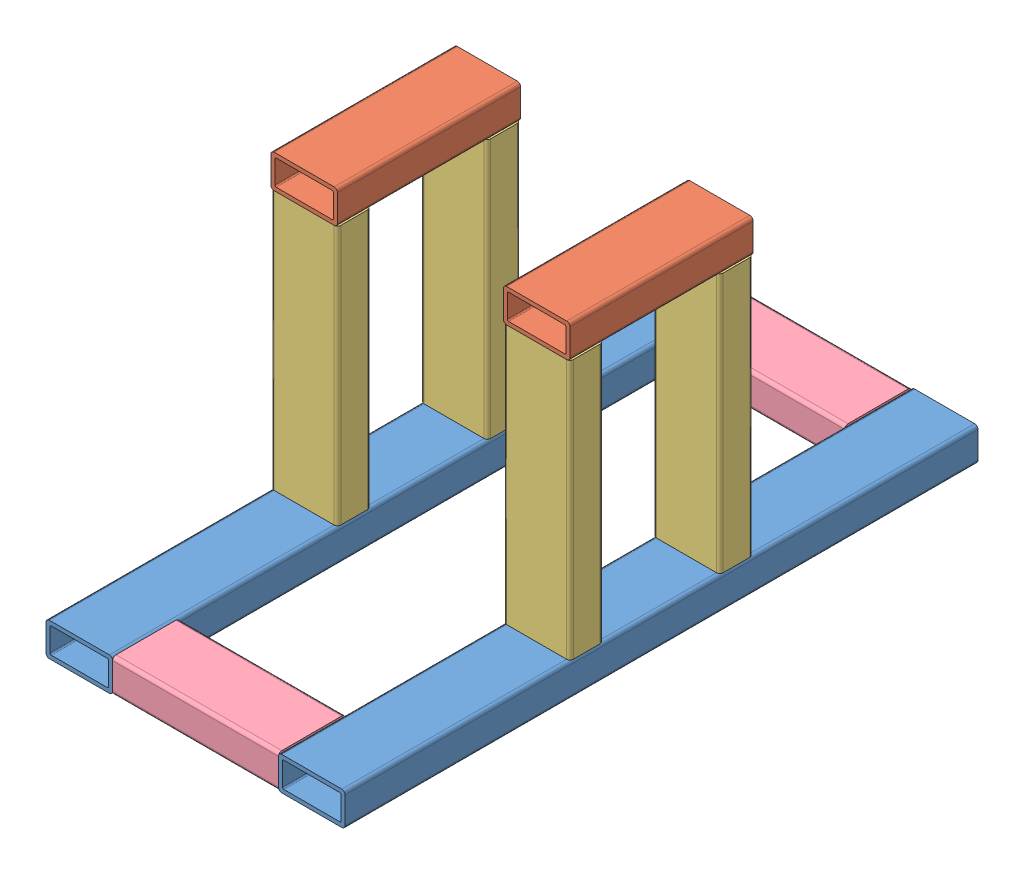
SolidWorks assembly Stand Assembly, configuration Default. Lengths in mm.
Overall size (228.08 248.72 482.6).
10 component instances, 4 part files, 29 mates.
Components (placement in the parent):
- Stand Assembly - 1 by 2 inch-1: Stand Assembly - 1 by 2 inch [6527K991] at (233.4487 297.5051 247.6284) size (50.8 25.4 482.6)
- Stand Assembly - 1 by 2 inch for bearing horizontal-2: Stand Assembly - 1 by 2 inch for bearing horizontal [6527K991] at (233.4487 520.8244 419.0784) size (50.8 25.4 139.7)
- Stand Assembly - 1 by 2 inch for bearing vertical-1: Stand Assembly - 1 by 2 inch for bearing vertical [6527K991] at (233.4487 310.2051 546.0784) x (1 0 0) z (0 1 0) size (50.8 25.4 197.92)
- Stand Assembly - 1 by 2 inch for bearing vertical-2: Stand Assembly - 1 by 2 inch for bearing vertical [6527K991] at (233.4487 310.2051 431.7784) x (1 0 0) z (0 1 0) size (50.8 25.4 197.92)
- Stand Assembly - 1 by 2 inch side support-1: Stand Assembly - 1 by 2 inch side support [6527K991] at (385.3306 297.5051 704.8284) x (0 0 1) z (-1 0 0) size (50.8 25.4 126.48)
- Stand Assembly - 1 by 2 inch side support-2: Stand Assembly - 1 by 2 inch side support [6527K991] at (385.3306 297.5051 273.0284) x (0 0 1) z (-1 0 0) size (50.8 25.4 126.48)
- Stand Assembly - 1 by 2 inch for bearing horizontal-4: Stand Assembly - 1 by 2 inch for bearing horizontal [6527K991] at (410.7306 520.8244 419.0784) size (50.8 25.4 139.7)
- Stand Assembly - 1 by 2 inch for bearing vertical-3: Stand Assembly - 1 by 2 inch for bearing vertical [6527K991] at (410.7306 310.2051 546.0784) x (1 0 0) z (0 1 0) size (50.8 25.4 197.92)
- Stand Assembly - 1 by 2 inch for bearing vertical-4: Stand Assembly - 1 by 2 inch for bearing vertical [6527K991] at (410.7306 310.2051 431.7784) x (1 0 0) z (0 1 0) size (50.8 25.4 197.92)
- Stand Assembly - 1 by 2 inch-2: Stand Assembly - 1 by 2 inch [6527K991] at (410.7306 297.5051 247.6284) size (50.8 25.4 482.6)
Mates (geometry in assembly coordinates):
- Coincident1: coincident anti-aligned: plane of Stand Assembly - 1 by 2 inch for bearing horizontal-2 through (256.3087 508.1244 558.7784) normal (0 -1 0); plane of Stand Assembly - 1 by 2 inch for bearing vertical-2 through (256.3087 508.1244 441.9384) normal (0 1 0)
- Coincident2: coincident anti-aligned: plane of Stand Assembly - 1 by 2 inch for bearing horizontal-2 through (256.3087 508.1244 558.7784) normal (0 -1 0); plane of Stand Assembly - 1 by 2 inch for bearing vertical-1 through (256.3087 508.1244 556.2384) normal (0 1 0)
- Coincident3: coincident aligned: line of Stand Assembly - 1 by 2 inch for bearing horizontal-2 through (210.5887 508.1244 558.7784) axis (1 0 0); line of Stand Assembly - 1 by 2 inch for bearing vertical-1 through (210.5887 508.1244 558.7784) axis (1 0 0)
- Coincident5: coincident anti-aligned: line of Stand Assembly - 1 by 2 inch for bearing horizontal-2 through (210.5887 508.1244 419.0784) axis (1 0 0); line of Stand Assembly - 1 by 2 inch for bearing vertical-2 through (256.3087 508.1244 419.0784) axis (-1 0 0)
- Coincident6: coincident anti-aligned: plane of Stand Assembly - 1 by 2 inch-1 through (256.3087 310.2051 730.2284) normal (0 1 0); plane of Stand Assembly - 1 by 2 inch for bearing vertical-2 through (256.3087 310.2051 441.9384) normal (0 -1 0)
- Coincident7: coincident anti-aligned: plane of Stand Assembly - 1 by 2 inch-1 through (256.3087 310.2051 730.2284) normal (0 1 0); plane of Stand Assembly - 1 by 2 inch for bearing vertical-1 through (256.3087 310.2051 556.2384) normal (0 -1 0)
- Coincident8: coincident: point of Stand Assembly - 1 by 2 inch for bearing horizontal-2; unknown of Stand Assembly - 1 by 2 inch for bearing vertical-1
- Coincident11: coincident: unknown of Stand Assembly - 1 by 2 inch for bearing horizontal-2; line of Stand Assembly - 1 by 2 inch for bearing vertical-2 through (256.3087 508.1244 419.0784) axis (-1 0 0)
- Coincident12: coincident: unknown of Stand Assembly - 1 by 2 inch for bearing horizontal-2; unknown of Stand Assembly - 1 by 2 inch for bearing vertical-2
- Coincident13: coincident anti-aligned: line of Stand Assembly - 1 by 2 inch-1 through (210.5887 310.2051 419.0784) axis (1 0 0); line of Stand Assembly - 1 by 2 inch for bearing vertical-2 through (256.3087 310.2051 419.0784) axis (-1 0 0)
- Coincident14: coincident: point of assembly; point of Stand Assembly - 1 by 2 inch-1; moEndPointRef_w of Stand Assembly - 1 by 2 inch for bearing vertical-2
- Coincident15: coincident anti-aligned: plane of Stand Assembly - 1 by 2 inch-1 through (258.8487 287.3451 730.2284) normal (1 0 0); plane of Stand Assembly - 1 by 2 inch side support-1 through (258.8487 287.3451 727.6884) normal (-1 0 0)
- Coincident16: coincident aligned: line of Stand Assembly - 1 by 2 inch-1 through (258.8487 287.3451 730.2284) axis (0 1 0); line of Stand Assembly - 1 by 2 inch side support-1 through (258.8487 287.3451 730.2284) axis (0 1 0)
- Coincident17: coincident aligned: plane of Stand Assembly - 1 by 2 inch-1 through (256.3087 310.2051 730.2284) normal (0 1 0); plane of Stand Assembly - 1 by 2 inch side support-1 through (258.8487 310.2051 727.6884) normal (0 1 0)
- Coincident19: coincident anti-aligned: plane of Stand Assembly - 1 by 2 inch-1 through (258.8487 287.3451 730.2284) normal (1 0 0); plane of Stand Assembly - 1 by 2 inch side support-2 through (258.8487 287.3451 295.8884) normal (-1 0 0)
- Coincident20: coincident aligned: plane of Stand Assembly - 1 by 2 inch-1 through (256.3087 310.2051 730.2284) normal (0 1 0); plane of Stand Assembly - 1 by 2 inch side support-2 through (258.8487 310.2051 295.8884) normal (0 1 0)
- Coincident21: coincident anti-aligned: line of Stand Assembly - 1 by 2 inch side support-2 through (258.8487 307.6651 247.6284) axis (0 -1 0); line of Stand Assembly - 1 by 2 inch-1 through (258.8487 287.3451 247.6284) axis (0 1 0)
- Coincident22: coincident anti-aligned: plane of Stand Assembly - 1 by 2 inch for bearing horizontal-4 through (433.5906 508.1244 558.7784) normal (0 -1 0); plane of Stand Assembly - 1 by 2 inch for bearing vertical-4 through (433.5906 508.1244 441.9384) normal (0 1 0)
- Coincident24: coincident anti-aligned: plane of Stand Assembly - 1 by 2 inch for bearing horizontal-4 through (433.5906 508.1244 558.7784) normal (0 -1 0); plane of Stand Assembly - 1 by 2 inch for bearing vertical-3 through (433.5906 508.1244 556.2384) normal (0 1 0)
- Coincident25: coincident aligned: line of Stand Assembly - 1 by 2 inch for bearing horizontal-4 through (387.8706 508.1244 558.7784) axis (1 0 0); line of Stand Assembly - 1 by 2 inch for bearing vertical-3 through (387.8706 508.1244 558.7784) axis (1 0 0)
- Coincident26: coincident aligned: plane of Stand Assembly - 1 by 2 inch for bearing horizontal-4 through (436.1306 510.6644 558.7784) normal (1 0 0); plane of Stand Assembly - 1 by 2 inch for bearing vertical-3 through (436.1306 508.1244 556.2384) normal (1 0 0)
- Coincident27: coincident: unknown of Stand Assembly - 1 by 2 inch for bearing horizontal-4; line of Stand Assembly - 1 by 2 inch for bearing vertical-4 through (433.5906 508.1244 419.0784) axis (-1 0 0)
- Coincident28: coincident aligned: plane of Stand Assembly - 1 by 2 inch for bearing horizontal-4 through (436.1306 510.6644 558.7784) normal (1 0 0); plane of Stand Assembly - 1 by 2 inch for bearing vertical-4 through (436.1306 508.1244 441.9384) normal (1 0 0)
- Coincident29: coincident aligned: plane of Stand Assembly - 1 by 2 inch side support-1 through (258.8487 310.2051 727.6884) normal (0 1 0); plane of Stand Assembly - 1 by 2 inch-2 through (433.5906 310.2051 730.2284) normal (0 1 0)
- Coincident30: coincident anti-aligned: line of Stand Assembly - 1 by 2 inch side support-1 through (385.3306 287.3451 730.2284) axis (0 1 0); line of Stand Assembly - 1 by 2 inch-2 through (385.3306 307.6651 730.2284) axis (0 -1 0)
- Coincident31: coincident aligned: line of Stand Assembly - 1 by 2 inch side support-2 through (385.3306 307.6651 247.6284) axis (0 -1 0); line of Stand Assembly - 1 by 2 inch-2 through (385.3306 307.6651 247.6284) axis (0 -1 0)
- Coincident32: coincident anti-aligned: line of Stand Assembly - 1 by 2 inch for bearing vertical-4 through (433.5906 310.2051 419.0784) axis (-1 0 0); line of Stand Assembly - 1 by 2 inch-2 through (387.8706 310.2051 419.0784) axis (1 0 0)
- Coincident33: coincident: unknown of Stand Assembly - 1 by 2 inch for bearing vertical-4
- Coincident34: coincident anti-aligned: plane of Stand Assembly - 1 by 2 inch for bearing vertical-3 through (433.5906 310.2051 556.2384) normal (0 -1 0); plane of Stand Assembly - 1 by 2 inch-2 through (433.5906 310.2051 730.2284) normal (0 1 0)
